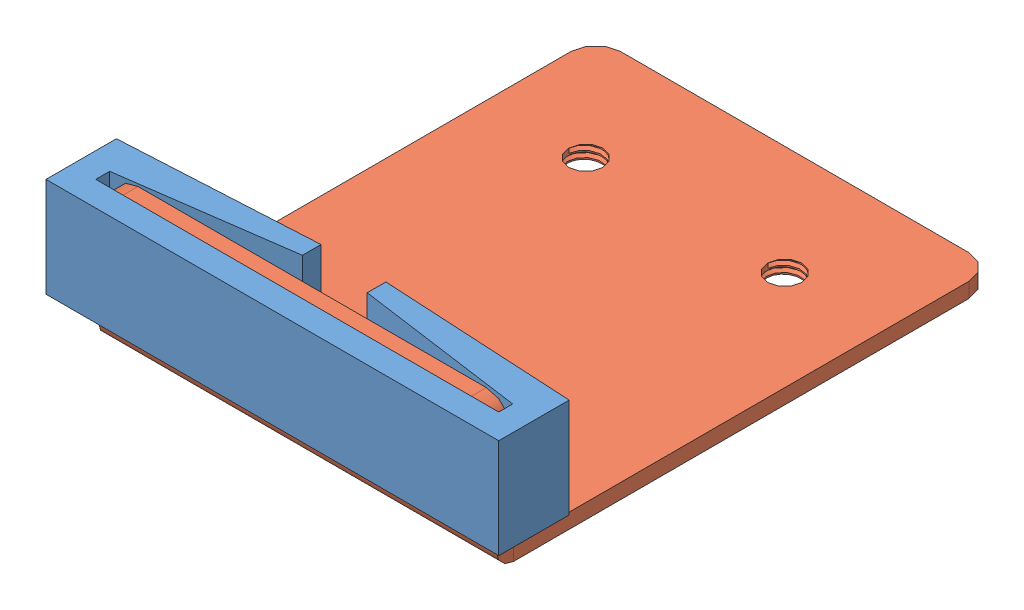
SolidWorks assembly B44-4B, configuration Default. Lengths in mm.
Overall size (91 28.42 105).
2 component instances, 2 part files, 0 mates.
Components (placement in the parent):
- G2305--1: G2305- [Default] at (0 15 0) size (91 20 16.3)
- A-0028218(Default)-1: A-0028218(Default) [Default] at (-40 25 0) size (80 28.42 100)
